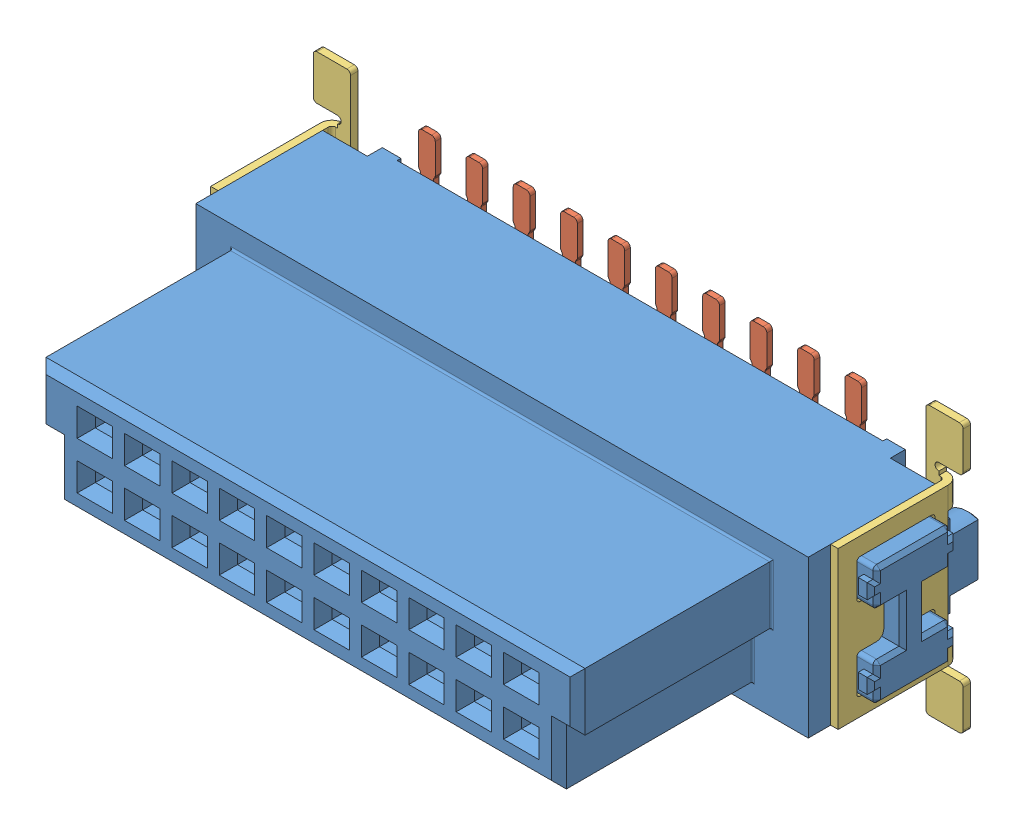
SolidWorks assembly m55-6012042_asm, configuration Default. Lengths in mm.
Overall size (17.78 7.2 9.8).
25 component instances, 4 part files, 0 mates.
Components (placement in the parent):
- m55-6012042_asm.stp-1: m55-6012042_asm.stp [Default] at origin size (17.78 7.2 11.05)
  - M55-60120_MOULD.stp-1: M55-60120_MOULD.stp [Default] at origin size (17.78 4.2 9.8)
  - M55-601_CONTACT.stp-1: M55-601_CONTACT.stp [Default] at (-5.715 0.635 0.4) x (1 0 0) z (0 -1 0) size (1.05 8.04 3.02)
  - M55-601_CONTACT.stp-2: M55-601_CONTACT.stp [Default] at (-4.445 0.635 0.4) x (1 0 0) z (0 -1 0) size (1.05 8.04 3.02)
  - M55-601_CONTACT.stp-3: M55-601_CONTACT.stp [Default] at (-3.175 0.635 0.4) x (1 0 0) z (0 -1 0) size (1.05 8.04 3.02)
  - M55-601_CONTACT.stp-4: M55-601_CONTACT.stp [Default] at (-1.905 0.635 0.4) x (1 0 0) z (0 -1 0) size (1.05 8.04 3.02)
  - M55-601_CONTACT.stp-5: M55-601_CONTACT.stp [Default] at (-0.635 0.635 0.4) x (1 0 0) z (0 -1 0) size (1.05 8.04 3.02)
  - M55-601_CONTACT.stp-6: M55-601_CONTACT.stp [Default] at (0.635 0.635 0.4) x (1 0 0) z (0 -1 0) size (1.05 8.04 3.02)
  - M55-601_CONTACT.stp-7: M55-601_CONTACT.stp [Default] at (1.905 0.635 0.4) x (1 0 0) z (0 -1 0) size (1.05 8.04 3.02)
  - M55-601_CONTACT.stp-8: M55-601_CONTACT.stp [Default] at (3.175 0.635 0.4) x (1 0 0) z (0 -1 0) size (1.05 8.04 3.02)
  - M55-601_CONTACT.stp-9: M55-601_CONTACT.stp [Default] at (4.445 0.635 0.4) x (1 0 0) z (0 -1 0) size (1.05 8.04 3.02)
  - M55-601_CONTACT.stp-10: M55-601_CONTACT.stp [Default] at (5.715 0.635 0.4) x (1 0 0) z (0 -1 0) size (1.05 8.04 3.02)
  - M55-601_CONTACT.stp-11: M55-601_CONTACT.stp [Default] at (-5.715 -0.635 0.4) x (-1 0 0) z (0 1 0) size (1.05 8.04 3.02)
  - M55-601_CONTACT.stp-12: M55-601_CONTACT.stp [Default] at (-4.445 -0.635 0.4) x (-1 0 0) z (0 1 0) size (1.05 8.04 3.02)
  - M55-601_CONTACT.stp-13: M55-601_CONTACT.stp [Default] at (-3.175 -0.635 0.4) x (-1 0 0) z (0 1 0) size (1.05 8.04 3.02)
  - M55-601_CONTACT.stp-14: M55-601_CONTACT.stp [Default] at (-1.905 -0.635 0.4) x (-1 0 0) z (0 1 0) size (1.05 8.04 3.02)
  - M55-601_CONTACT.stp-15: M55-601_CONTACT.stp [Default] at (-0.635 -0.635 0.4) x (-1 0 0) z (0 1 0) size (1.05 8.04 3.02)
  - M55-601_CONTACT.stp-16: M55-601_CONTACT.stp [Default] at (0.635 -0.635 0.4) x (-1 0 0) z (0 1 0) size (1.05 8.04 3.02)
  - M55-601_CONTACT.stp-17: M55-601_CONTACT.stp [Default] at (1.905 -0.635 0.4) x (-1 0 0) z (0 1 0) size (1.05 8.04 3.02)
  - M55-601_CONTACT.stp-18: M55-601_CONTACT.stp [Default] at (3.175 -0.635 0.4) x (-1 0 0) z (0 1 0) size (1.05 8.04 3.02)
  - M55-601_CONTACT.stp-19: M55-601_CONTACT.stp [Default] at (4.445 -0.635 0.4) x (-1 0 0) z (0 1 0) size (1.05 8.04 3.02)
  - M55-601_CONTACT.stp-20: M55-601_CONTACT.stp [Default] at (5.715 -0.635 0.4) x (-1 0 0) z (0 1 0) size (1.05 8.04 3.02)
  - M55-700_STRAP.stp-1: M55-700_STRAP.stp [Default] at (8.21 0 -0.05) x (-1 0 0) z (0 1 0) size (1 3.25 7.2)
  - M55-700_STRAP.stp-2: M55-700_STRAP.stp [Default] at (-8.21 0 -0.05) x (1 0 0) z (0 -1 0) size (1 3.25 7.2)
  - M55-600_CAP.stp-1: M55-600_CAP.stp [Default] at (0 0 10.25) x (0 -1 0) z (-1 0 0) size (4.75 4.25 8) (hidden)
